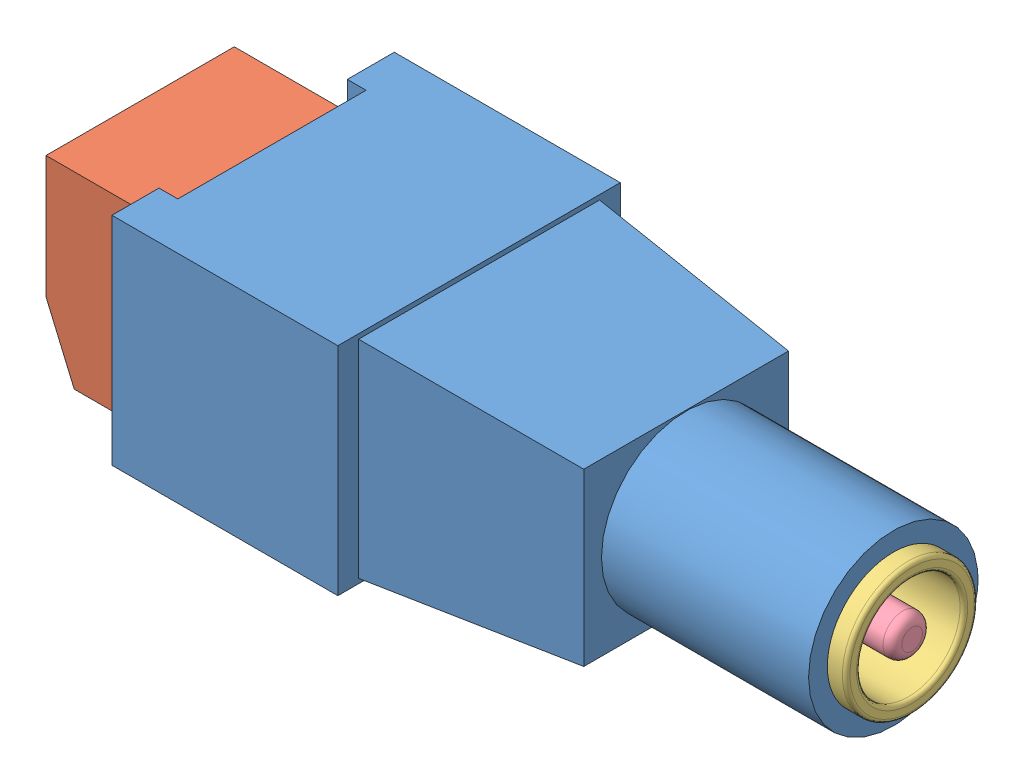
SolidWorks assembly dc_power_jack_assembly, configuration Default. Lengths in mm.
Overall size (41 11.5 15).
10 component instances, 6 part files, 15 mates.
Components (placement in the parent):
- main_body-1: main_body [Default] at (-16.1052 -4.2602 1.6818) size (34 11.5 15)
- green_screw_section-1: green_screw_section [Default] at (-21.1052 -4.2602 6.6818) x (-1 0 0) z (0 0 -1) size (7 10 10)
- jack_outer_metal-1: jack_outer_metal [Default] at (0.8948 1.4898 1.6818) x (0 0.735968 -0.677016) z (1 0 0) size (7 7 12)
- jack_inner_rod-1: jack_inner_rod [Default] at (0.8948 1.4898 1.6818) x (0 0 -1) z (1 0 0) size (2.1 2.1 12)
- wireholder_with_screw_assembly-1: wireholder_with_screw_assembly [Default] at (4.4628 17.1409 -69.445) x (0 0 -1) z (-1 0 0) size (4 9.26 5)
  - wireholder-1: wireholder [Default] at (-75.1268 12.4011 26.568) size (4 5.5 5)
  - pan cross head_ai-1: pan cross head_ai [CR-PHMS 0.06-80x0.125x0.125-N] at (-73.6268 21.1937 29.068) x (0 -1 0) z (0 0 1) size (4.26 2.95 2.95)
- wireholder_with_screw_assembly-2: wireholder_with_screw_assembly [Default] at (4.4628 17.1409 -74.445) x (0 0 -1) z (-1 0 0) size (4 9.26 5)
  - wireholder-1: wireholder [Default] at (-75.1268 12.4011 26.568) size (4 5.5 5)
  - pan cross head_ai-1: pan cross head_ai [CR-PHMS 0.06-80x0.125x0.125-N] at (-73.6268 21.1937 29.068) x (0 -1 0) z (0 0 1) size (4.26 2.95 2.95)
Mates (geometry in assembly coordinates):
- Concentric2: concentric aligned: cylinder of main_body-1 through (11.8948 1.4898 1.6818) axis (-1 0 0) radius 3.5; cylinder of jack_outer_metal-1 through (12.8948 1.4898 1.6818) axis (-1 0 0) radius 2.75
- Coincident2: coincident anti-aligned: plane of main_body-1 through (0.8948 -4.2602 1.6818) normal (1 0 0); plane of jack_outer_metal-1 through (0.8948 1.4898 1.6818) normal (-1 0 0)
- Concentric3: concentric aligned: cylinder of jack_outer_metal-1 through (12.8948 1.4898 1.6818) axis (-1 0 0) radius 2.75; cylinder of jack_inner_rod-1 through (12.8948 1.4898 1.6818) axis (-1 0 0) radius 1.05
- Coincident3: coincident anti-aligned: plane of main_body-1 through (0.8948 -4.2602 1.6818) normal (1 0 0); plane of jack_inner_rod-1 through (0.8948 1.4898 1.6818) normal (-1 0 0)
- Parallel1: parallel anti-aligned: plane of main_body-1 through (-21.1052 7.2398 6.6818) normal (-1 0 0); plane of green_screw_section-1 through (-21.1052 -4.2602 -3.3182) normal (1 0 0)
- Coincident5: coincident anti-aligned: plane of main_body-1 through (-22.1052 7.2398 6.6818) normal (0 0 -1); plane of green_screw_section-1 through (-21.1052 -4.2602 6.6818) normal (0 0 1)
- Coincident6: coincident anti-aligned: plane of main_body-1 through (-21.1052 7.2398 6.6818) normal (-1 0 0); plane of green_screw_section-1 through (-21.1052 -4.2602 -3.3182) normal (1 0 0)
- Coincident7: coincident aligned: plane of main_body-1 through (-16.1052 -4.2602 1.6818) normal (0 -1 0); plane of green_screw_section-1 through (-26.6052 -4.2602 -3.3182) normal (0 -1 0)
- Parallel3: parallel aligned: plane of green_screw_section-1 through (-28.1052 5.7398 -3.3182) normal (-1 0 0); plane of wireholder_with_screw_assembly-1/wireholder-1 through (-27.1052 4.7398 5.6818) normal (-1 0 0)
- Coincident9: coincident anti-aligned: plane of green_screw_section-1 through (-21.1042 5.2398 2.1818) normal (0 -1 0); plane of wireholder_with_screw_assembly-1/wireholder-1 through (-27.1052 5.2398 5.6818) normal (0 1 0)
- Coincident10: coincident anti-aligned: plane of green_screw_section-1 through (-21.1042 5.2398 6.1818) normal (0 0 -1); plane of wireholder_with_screw_assembly-1/wireholder-1 through (-27.1052 4.7398 6.1818) normal (0 0 1)
- Concentric4: concentric anti-aligned: cylinder of green_screw_section-1 through (-24.6052 -4.2612 4.1818) axis (0 1 0) radius 1.5; cylinder of wireholder_with_screw_assembly-1/pan cross head_ai-1 through (-24.6052 -29.4528 4.1818) axis (0 -1 0) radius 0.762
- Coincident11: coincident anti-aligned: plane of green_screw_section-1 through (-21.1042 5.2398 -2.8182) normal (0 -1 0); plane of wireholder_with_screw_assembly-2/wireholder-1 through (-27.1052 5.2398 0.6818) normal (0 1 0)
- Coincident12: coincident anti-aligned: plane of green_screw_section-1 through (-21.1042 5.2398 -2.8182) normal (0 0 1); plane of wireholder_with_screw_assembly-2/wireholder-1 through (-27.1052 4.7398 -2.8182) normal (0 0 -1)
- Concentric5: concentric anti-aligned: cylinder of green_screw_section-1 through (-24.6052 -4.2612 -0.8182) axis (0 1 0) radius 1.5; cylinder of wireholder_with_screw_assembly-2/pan cross head_ai-1 through (-24.6052 -29.4528 -0.8182) axis (0 -1 0) radius 0.762
